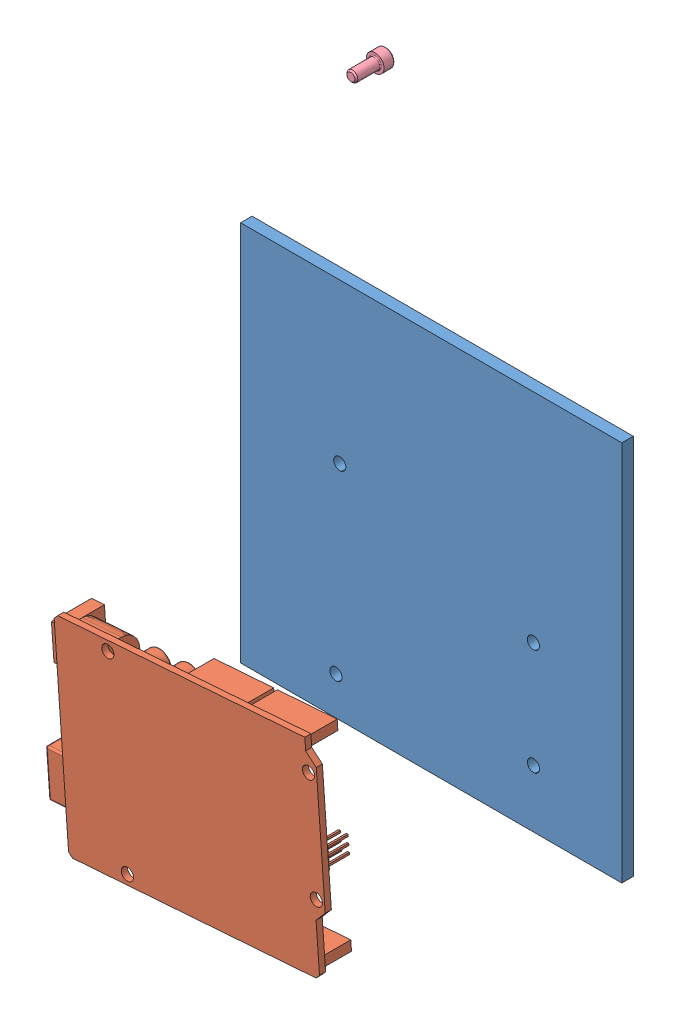
SolidWorks assembly cube assm, configuration Default. Lengths in mm.
Overall size (100 159.43 74.71).
7 component instances, 4 part files, 9 mates.
Components (placement in the parent):
- Side-1: Side [Default] at (33.5517 56.6781 74.1987) size (100 100 3)
- ArduinoUno-1: ArduinoUno [Default] at (28.4517 28.2218 136.2073) x (0.997288 0.073593 0) z (-0.073593 0.997288 0) size (74.8 12.1 53.3)
- .25x.5 Aluminum Hex Female Female Standoff-1: .25x.5 Aluminum Hex Female Female Standoff [Default] at (9.5592 64.9676 67.8487) x (-0.833482 0.552546 0) z (0 0 -1) size (6.35 8.06 12.7)
- .25x.5 Aluminum Hex Female Female Standoff-2: .25x.5 Aluminum Hex Female Female Standoff [Default] at (8.5517 16.6781 67.8487) x (1 0 0) z (0 0 -1) size (6.35 8.06 12.7)
- .25x.5 Aluminum Hex Female Female Standoff-3: .25x.5 Aluminum Hex Female Female Standoff [Default] at (60.3592 21.7781 67.8487) x (1 0 0) z (0 0 -1) size (6.35 8.06 12.7)
- .25x.5 Aluminum Hex Female Female Standoff-4: .25x.5 Aluminum Hex Female Female Standoff [Default] at (60.3592 49.6781 67.8487) x (0.790862 -0.611994 0) z (0 0 -1) size (6.35 8.06 12.7)
- socket head cap screw_ai-12: socket head cap screw_ai [HX-SHCS 0.112-40x0.25x0.25-N] at (14.1164 155.8682 69.6318) x (0 0 1) z (-1 0 0) size (9.19 4.65 4.65)
Mates (geometry in assembly coordinates):
- Concentric13: concentric: cylinder of ArduinoUno-1 through (60.3592 49.6781 134.6073) axis (0 0 1) radius 1.6; cone of .25x.5 Aluminum Hex Female Female Standoff-4 through (60.3592 49.6781 61.4987) axis (0 0 1)
- Concentric16: concentric: circle of Side-1; circle of .25x.5 Aluminum Hex Female Female Standoff-1
- Coincident18: coincident: plane of Side-1 through (33.5517 56.6781 74.1987) normal (0 0 -1); plane of .25x.5 Aluminum Hex Female Female Standoff-1 through (9.5592 64.9676 74.1987) normal (0 0 1)
- Concentric20: concentric: circle of Side-1; circle of .25x.5 Aluminum Hex Female Female Standoff-4
- Coincident19: coincident: plane of Side-1 through (33.5517 56.6781 74.1987) normal (0 0 -1); plane of .25x.5 Aluminum Hex Female Female Standoff-4 through (60.3592 49.6781 74.1987) normal (0 0 1)
- Concentric21: concentric: circle of Side-1; circle of .25x.5 Aluminum Hex Female Female Standoff-3
- Coincident20: coincident: plane of Side-1 through (33.5517 56.6781 74.1987) normal (0 0 -1); plane of .25x.5 Aluminum Hex Female Female Standoff-3 through (60.3592 21.7781 74.1987) normal (0 0 1)
- Concentric22: concentric: circle of Side-1; circle of .25x.5 Aluminum Hex Female Female Standoff-2
- Coincident21: coincident: plane of Side-1 through (33.5517 56.6781 74.1987) normal (0 0 -1); plane of .25x.5 Aluminum Hex Female Female Standoff-2 through (8.5517 16.6781 74.1987) normal (0 0 1)
